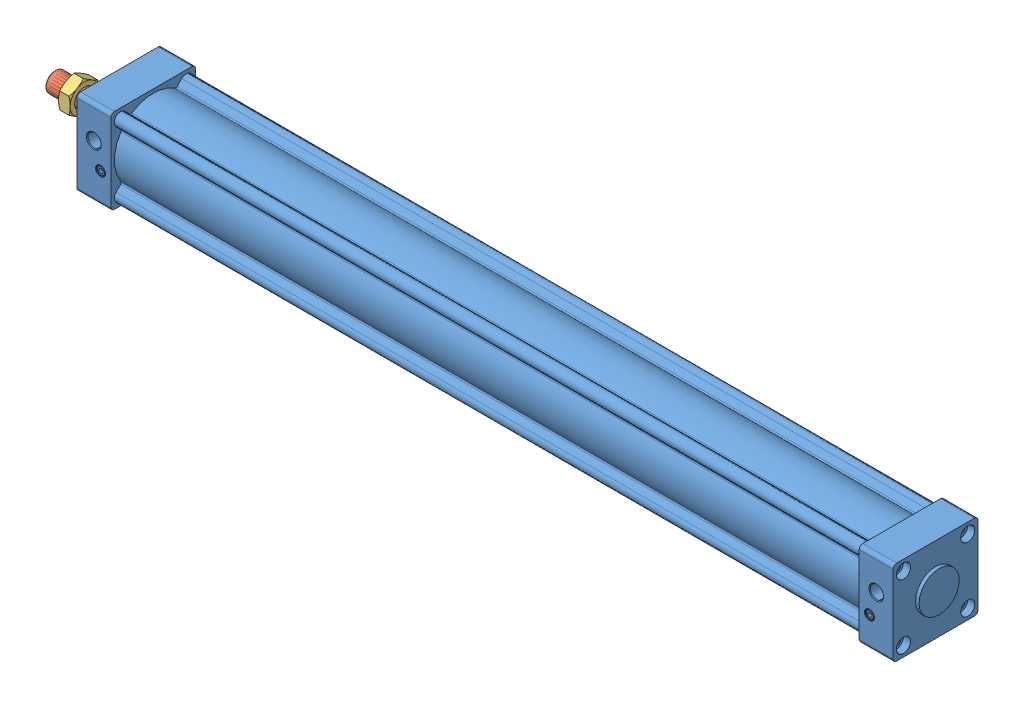
SolidWorks assembly JSI80x800S(000)+(), configuration 默认. Lengths in mm.
Overall size (990 95 95).
3 component instances, 3 part files, 6 mates.
Components (placement in the parent):
- JSI-80x800-S- (0) c-1: JSI-80x800-S- (0) c [默认] at origin size (938 95 95)
- JSI JSID JSIJ POLE 80JSI8000-1: JSI JSID JSIJ POLE 80JSI8000 [默认] at (-20 0 0) x (0 0 -1) z (-1 0 0) size (79 79 951.5)
- JSI-80-M22x1_5 - Nut-1: JSI-80-M22x1_5 - Nut [默认] at (-52 0 0) size (13 36.95 32)
Mates (geometry in assembly coordinates):
- 重合1: coincident anti-aligned: line of JSI-80x800-S- (0) c-1 through (161.8 -80.9 0) axis (0 1 0); line of JSI JSID JSIJ POLE 80JSI8000-1 through (161.8 60.9 0) axis (0 -1 0)
- 角度3: planar angle = 0 rad aligned: plane of JSI JSID JSIJ POLE 80JSI8000-1; plane of JSI-80x800-S- (0) c-1 through (0 0 0) normal (0 0 -1)
- 重合2: coincident anti-aligned: line of JSI JSID JSIJ POLE 80JSI8000-1 through (161.8 -100.9 0) axis (0 1 0); line of JSI-80-M22x1_5 - Nut-1 through (161.8 28.9 0) axis (0 -1 0)
- 角度6: planar angle = 0 rad aligned: plane of JSI-80-M22x1_5 - Nut-1 through (-52 0 0) normal (0 0 -1); plane of JSI JSID JSIJ POLE 80JSI8000-1
- LimitDistance1: limit distance = 72 mm aligned: plane of JSI JSID JSIJ POLE 80JSI8000-1 through (-72 0 0) normal (-1 0 0); plane of JSI-80x800-S- (0) c-1 through (0 -43.5 43.5) normal (-1 0 0)
- 距离2: distance = 20 mm aligned: plane of JSI-80-M22x1_5 - Nut-1 through (-52 0 0) normal (-1 0 0); plane of JSI JSID JSIJ POLE 80JSI8000-1 through (-72 0 0) normal (-1 0 0)
